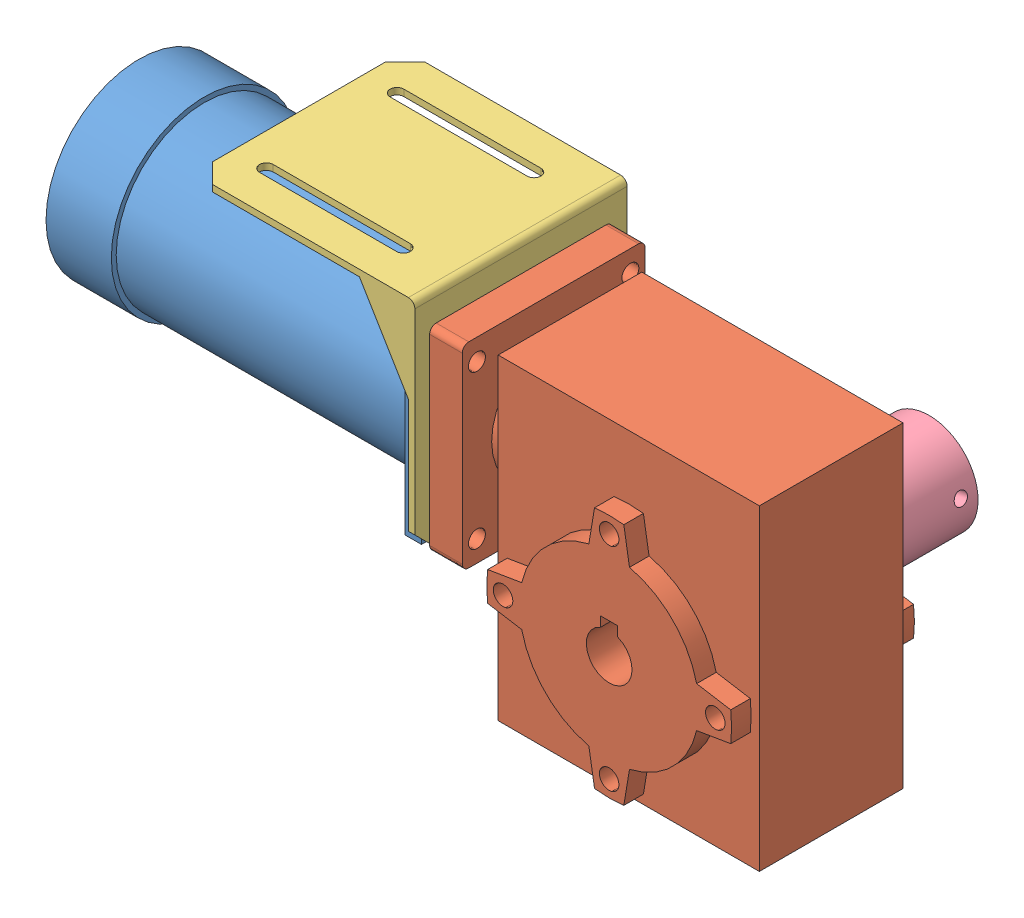
SolidWorks assembly 电机整套, configuration 默认. Lengths in mm.
Overall size (212 109 102.5).
5 component instances, 5 part files, 9 mates.
Components (placement in the parent):
- 电机-1: 电机 [默认] at (7.9512 16.5957 136) size (136 57 57)
- 减速器-1: 减速器 [默认] at (54.7667 -0.0575 136) size (95 100 56)
- 电机安装支架-2: 电机安装支架 [默认] at (9.9512 55.5957 136) x (0 0 -1) z (-1 0 0) size (65 68 68)
- 联轴器-2: 联轴器 [默认] at (67.2849 -12.9713 66) x (0.182402 -0.983224 0) z (0 0 1) size (30 30 42)
- 14mm输出轴-1: 14mm输出轴 [默认] at (76.5366 -30.9692 88) size (14 14 30)
Mates (geometry in assembly coordinates):
- 同心2: concentric aligned: circle of 电机-1; cylinder of 减速器-1 through (9.9512 40.0957 159.5) axis (1 0 0) radius 2.6
- 同心4: concentric anti-aligned: cylinder of 电机-1 through (9.4512 16.5957 136) axis (-1 0 0) radius 19; cylinder of 电机安装支架-2 through (-58.0488 16.5957 136) axis (1 0 0) radius 19.1
- 重合4: coincident anti-aligned: plane of 电机-1 through (7.9512 16.5957 136) normal (1 0 0); plane of 电机安装支架-2 through (7.9512 -12.4043 103.5) normal (-1 0 0)
- 同心6: concentric aligned: cylinder of 减速器-1 through (64.9512 -13.4043 48) axis (0 0 1) radius 7; cylinder of 联轴器-2 through (64.9512 -13.4043 88) axis (0 0 1) radius 7
- 同心7: concentric anti-aligned: cylinder of 电机-1 through (28.9512 16.5957 136) axis (-1 0 0) radius 4; cylinder of 减速器-1 through (19.9512 16.5957 136) axis (1 0 0) radius 4
- 重合6: coincident anti-aligned: plane of 减速器-1 through (9.9512 44.5957 162) normal (-1 0 0); plane of 电机安装支架-2 through (9.9512 55.5957 103.5) normal (1 0 0)
- 重合7: coincident anti-aligned: plane of 联轴器-2 through (64.9512 -13.4043 88) normal (0 0 1); plane of 14mm输出轴-1 through (64.9512 -13.4043 88) normal (0 0 -1)
- 同心8: concentric anti-aligned: cylinder of 减速器-1 through (64.9512 -13.4043 48) axis (0 0 1) radius 7; cylinder of 14mm输出轴-1 through (64.9512 -13.4043 118) axis (0 0 -1) radius 7
- 重合8: coincident anti-aligned: plane of 减速器-1 through (64.9512 -13.4043 108) normal (0 0 -1); plane of 联轴器-2 through (64.9512 -13.4043 108) normal (0 0 1)
